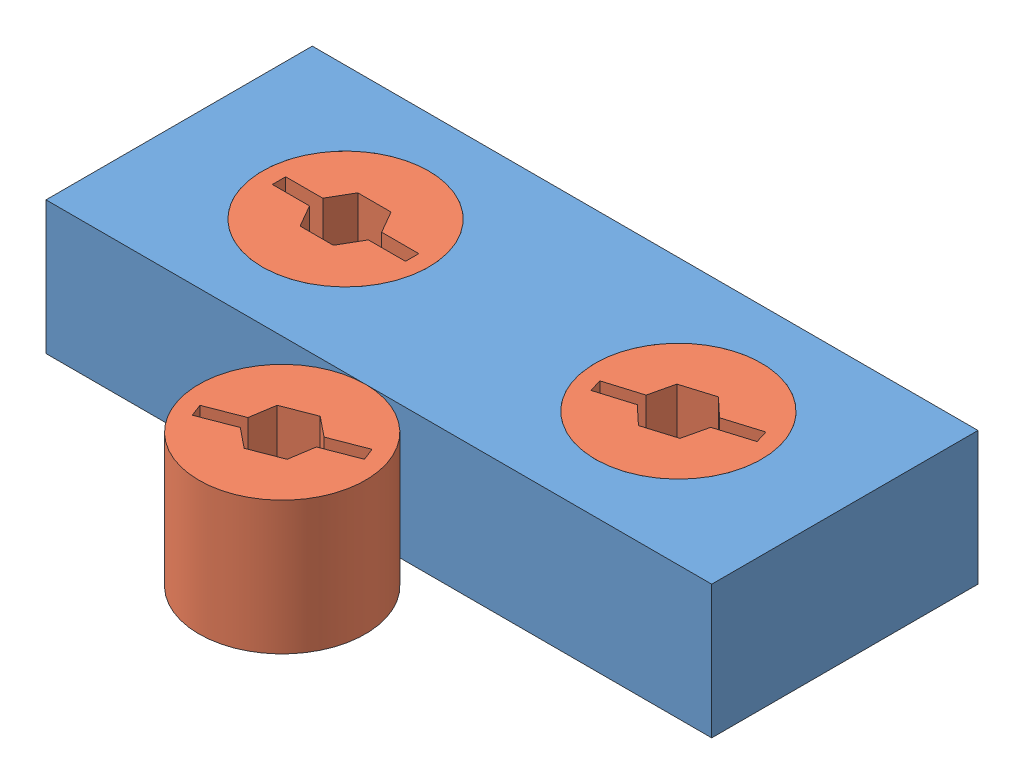
SolidWorks assembly Assembly 60, configuration Default. Lengths in mm.
Overall size (127 25.4 87.2).
4 component instances, 2 part files, 7 mates.
Components (placement in the parent):
- Block_circles_2013-1: Block_circles_2013 [Default] at (-5.9982 51.4786 118.9804) size (127 25.4 50.8)
- circles_2013-1: circles_2013 [Default] at (25.7518 51.4786 93.5804) size (31.75 25.4 31.75)
- circles_2013-2: circles_2013 [Default] at (89.2518 51.4786 93.5804) x (0.956786 0 -0.290794) z (0.290794 0 0.956786) size (31.75 25.4 31.75)
- circles_2013-3: circles_2013 [Default] at (54.9335 51.4786 134.8554) x (0.93301 0 -0.35985) z (0.35985 0 0.93301) size (31.75 25.4 31.75)
Mates (geometry in assembly coordinates):
- Concentric1: concentric anti-aligned: cylinder of Block_circles_2013-1 through (25.7518 51.4786 93.5804) axis (0 1 0) radius 15.875; cylinder of circles_2013-1 through (25.7518 76.8786 93.5804) axis (0 -1 0) radius 15.875
- Coincident1: coincident aligned: plane of Block_circles_2013-1 through (-5.9982 76.8786 118.9804) normal (0 1 0); plane of circles_2013-1 through (25.7518 76.8786 93.5804) normal (0 1 0)
- Parallel1: parallel aligned: plane of Block_circles_2013-1 through (-5.9982 76.8786 118.9804) normal (0 0 1); plane of circles_2013-1 through (25.7518 51.4786 88.0812) normal (0 0 1)
- Concentric2: concentric aligned: circle of Block_circles_2013-1; circle of circles_2013-2
- Coincident4: coincident aligned: plane of Block_circles_2013-1 through (-5.9982 76.8786 118.9804) normal (0 1 0); plane of circles_2013-2 through (89.2518 76.8786 93.5804) normal (0 1 0)
- Tangent3: tangent: plane of Block_circles_2013-1 through (-5.9982 76.8786 118.9804) normal (0 0 1); cylinder of circles_2013-3 through (54.9335 76.8786 134.8554) axis (0 -1 0) radius 15.875
- Coincident5: coincident aligned: plane of Block_circles_2013-1 through (-5.9982 76.8786 118.9804) normal (0 1 0); plane of circles_2013-3 through (54.9335 76.8786 134.8554) normal (0 1 0)
